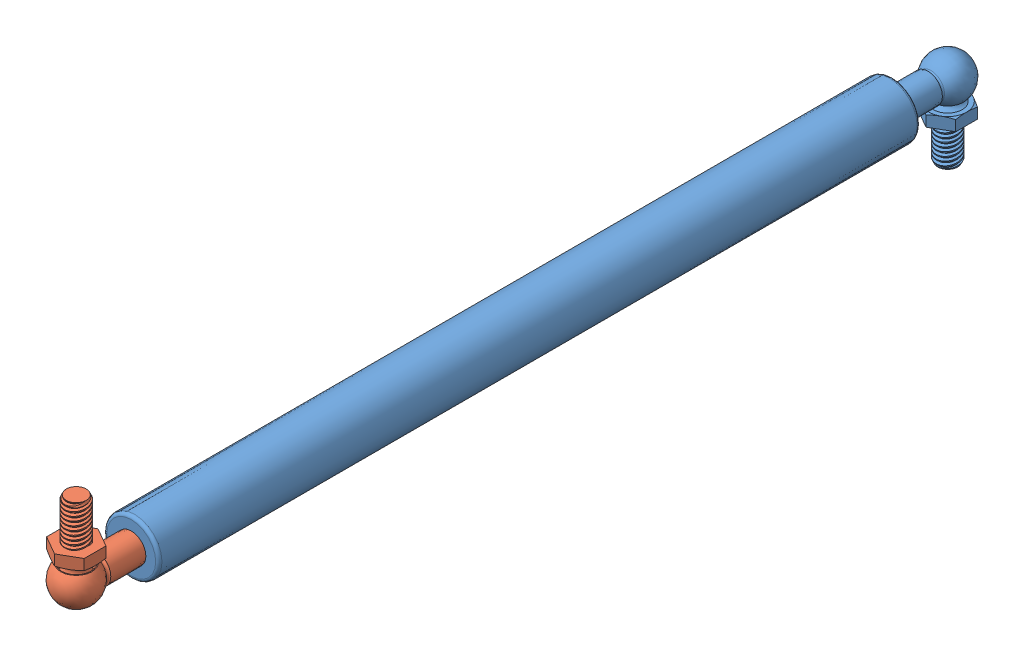
SolidWorks assembly 20in Gas Spring, configuration Default. Lengths in mm.
Overall size (19.05 51.25 316).
2 component instances, 2 part files, 3 mates.
Components (placement in the parent):
- 20in extended 8.27in retracted ball-joint end-Body-1: 20in extended 8.27in retracted ball-joint end-Body [Default] at (140.5365 160.2041 322.6238) size (19.05 35.15 289.5)
- 20in extended 8.27in retracted ball-joint end-Rod-1: 20in extended 8.27in retracted ball-joint end-Rod [Default] at (140.5365 160.2041 112.5658) x (-1 0 0) z (0 0 1) size (14.8 33.02 236.56)
Mates (geometry in assembly coordinates):
- Concentric1: concentric anti-aligned: cylinder of 20in extended 8.27in retracted ball-joint end-Body-1 through (140.5365 160.2041 578.1478) axis (0 0 1) radius 4.087; cylinder of 20in extended 8.27in retracted ball-joint end-Rod-1 through (140.5365 160.2041 349.0898) axis (0 0 -1) radius 3.937
- LimitDistance1: limit distance = 300.99 mm: line of 20in extended 8.27in retracted ball-joint end-Rod-1 through (140.5365 160.8124 368.0898) axis (0 1 0); line of 20in extended 8.27in retracted ball-joint end-Body-1 through (140.5365 160.2041 67.0998) axis (0 -1 0)
- Parallel1: parallel anti-aligned: cylinder of 20in extended 8.27in retracted ball-joint end-Body-1 through (140.5365 160.2041 67.0998) axis (0 -1 0) radius 5.1; cylinder of 20in extended 8.27in retracted ball-joint end-Rod-1 through (140.5365 160.2041 368.0898) axis (0 1 0) radius 5.1
